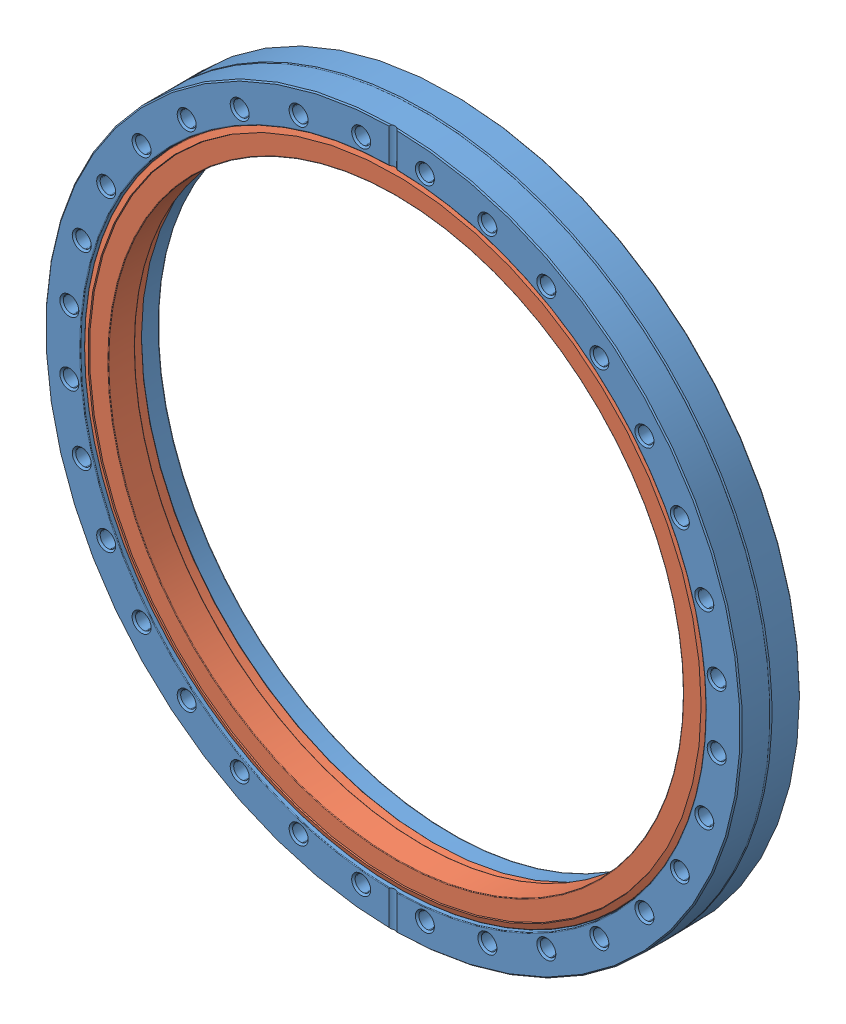
SolidWorks assembly DN_250, configuration Default. Lengths in mm.
Overall size (304.04 304.04 25.94).
2 component instances, 2 part files, 0 mates.
Components (placement in the parent):
- P0000462-1: P0000462 [Default] at (0 0 12.954) x (-1 0 0) z (0 0 -1) size (304.04 304.04 25.94)
- P0000519-1: P0000519 [Default] at (0 0 16.6243) size (272.64 272.64 17.25)
